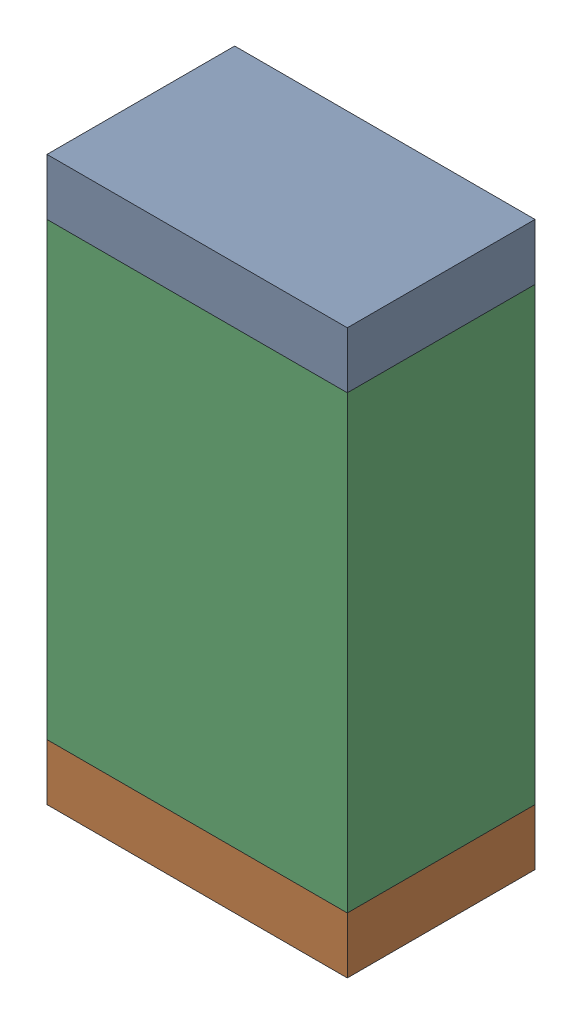
SolidWorks assembly R37, configuration Default. Lengths in mm.
Overall size (0.8 1.5 0.5).
6 component instances, 2 part files, 0 mates.
Components (placement in the parent):
- 810156592-1: 810156592 [Default] at (119.45 51.525 0) size (0.8 0.15 0.5)
  - Extruded_7-1: Extruded_7 [Default] at origin size (0.8 0.15 0.5)
- 810156592-2: 810156592 [Default] at (119.45 50.175 0) size (0.8 0.15 0.5)
  - Extruded_7-1: Extruded_7 [Default] at origin size (0.8 0.15 0.5)
- 810156976-1: 810156976 [Default] at (119.45 50.85 0) size (0.8 1.2 0.5)
  - Extruded_6-1: Extruded_6 [Default] at origin size (0.8 1.2 0.5)
